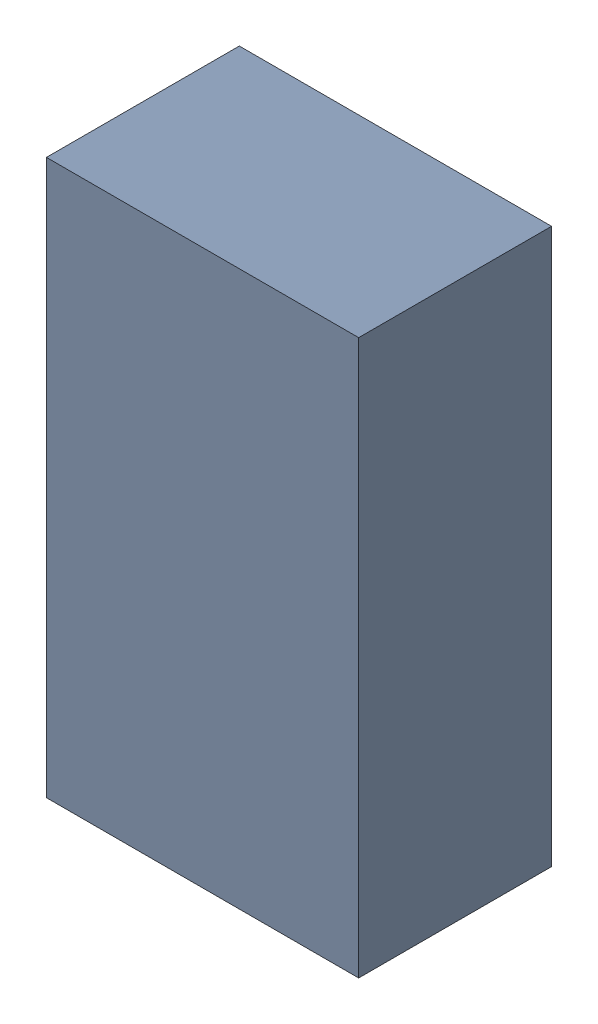
SolidWorks assembly U406PCB, configuration Default. Lengths in mm.
Overall size (2.59 4.6 1.6).
2 component instances, 1 part files, 0 mates.
Components (placement in the parent):
- 854785704-1: 854785704 [Default] at (93.1 87 -3.2638) size (2.59 4.6 1.6)
  - Extruded_8-1: Extruded_8 [Default] at origin size (2.59 4.6 1.6)
